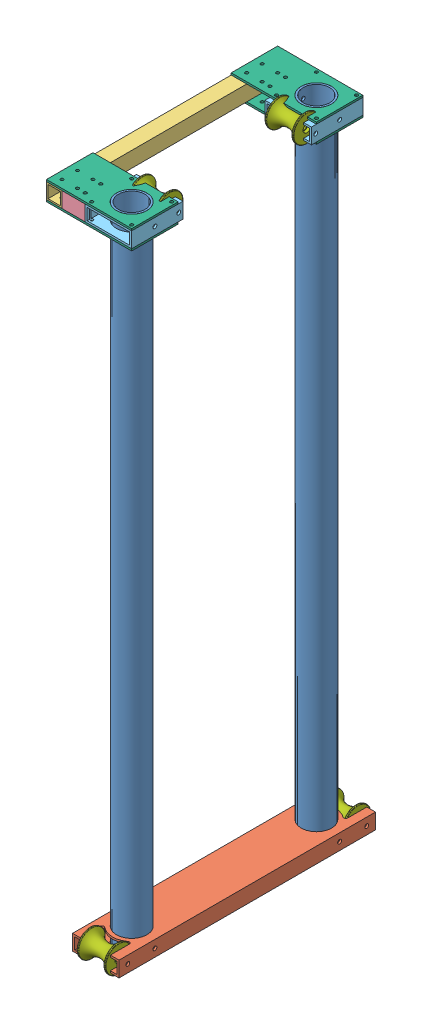
SolidWorks assembly 220-000 Second Stage Asm, configuration Default. Lengths in mm.
Overall size (139.7 1085.1 443.43).
17 component instances, 7 part files, 16 mates.
Components (placement in the parent):
- 220-002 Rod-1: 220-002 Rod [Default] at (79.1621 3.4691 -166.1788) x (0 0 1) z (-1 0 0) size (49.94 1054.1 49.94)
- 220-002 Rod-2: 220-002 Rod [Default] at (79.1621 3.4691 136.7848) x (0.387844 0 0.921725) z (-0.921725 0 0.387844) size (49.94 1054.1 49.94)
- 220-001n Second stage base-1: 220-001n Second stage base [Default] at (79.1621 16.1691 -225.0433) size (76.2 25.4 420.69)
- 221-000 Asm-1: 221-000 Asm [Default] at (2.9621 1028.9941 -14.697) x (-1 0 0) z (0 0 -1) size (139.7 61.76 379.16)
  - 221-003-1: 221-003 [Default] at origin size (25.4 25.4 379.16)
  - 221-002-1: 221-002 [Default] at (-19.05 25.4 189.5818) x (0 0 -1) z (-1 0 0) size (50.8 25.4 38.1)
  - 221-001-1: 221-001 [Default] at (-114.3 25.4 140.3058) x (1 0 0) z (0 1 0) size (76.2 84.26 25.4)
  - 221-001-2: 221-001 [Default] at (-114.3 0 -140.3058) x (1 0 0) z (0 -1 0) size (76.2 84.26 25.4)
  - 221-002-2: 221-002 [Default] at (-19.05 0 -189.5818) x (0 0 1) z (-1 0 0) size (50.8 25.4 38.1)
  - 221-004-1: 221-004 [Rev 1.1] at (0 25.4 0) x (1 0 0) z (0 1 0) size (139.7 76.2 3.17)
  - 221-004-2: 221-004 [Rev 1.1] at (0 25.4 302.9636) x (1 0 0) z (0 1 0) size (139.7 76.2 3.17)
  - 221-004-3: 221-004 [Rev 1.1] at (0 -3.175 0) x (1 0 0) z (0 1 0) size (139.7 76.2 3.17)
  - 221-004-4: 221-004 [Rev 1.1] at (0 -3.175 302.9636) x (1 0 0) z (0 1 0) size (139.7 76.2 3.17)
  - 200-001 Roller 3-1: 200-001 Roller 3 [Default] at (-76.2 12.7 -112.3658) x (0 -1 0) z (0 0 1) size (43.94 46.98 43.94)
  - 200-001 Roller 3-2: 200-001 Roller 3 [Default] at (-76.2 12.7 112.3658) x (0 -0.780395 0.625287) z (0 0.625287 0.780395) size (43.94 46.98 43.94)
- 200-001 Roller 3-1: 200-001 Roller 3 [Default] at (79.1621 16.1691 -210.6288) x (0 0.381849 -0.924225) z (0 -0.924225 -0.381849) size (43.94 46.98 43.94)
- 200-001 Roller 3-2: 200-001 Roller 3 [Default] at (79.1621 16.1691 181.2348) x (0 0.999115 0.042073) z (0 -0.042073 0.999115) size (43.94 46.98 43.94)
Mates (geometry in assembly coordinates):
- Concentric2: concentric: cylinder of 220-002 Rod-2 through (79.1621 1057.5691 136.7848) axis (0 -1 0) radius 24.972; cylinder of 221-000 Asm-1/221-004-1 through (79.1621 1057.5691 136.7848) axis (0 -1 0) radius 24.972
- Coincident1: coincident: plane of 220-002 Rod-2 through (79.1621 3.4691 136.7848) normal (0 -1 0); plane of 220-001n Second stage base-1 through (41.0621 3.4691 195.6493) normal (0 -1 0)
- Coincident2: coincident: plane of 220-002 Rod-1 through (79.1621 3.4691 -166.1788) normal (0 -1 0); plane of 220-001n Second stage base-1 through (41.0621 3.4691 195.6493) normal (0 -1 0)
- Coincident3: coincident: plane of 220-002 Rod-1 through (79.1621 1057.5691 -166.1788) normal (0 1 0); plane of 221-000 Asm-1/221-004-2 through (2.9621 1057.5691 -317.6606) normal (0 1 0)
- Concentric3: concentric: cylinder of 220-002 Rod-2 through (79.1621 1057.5691 136.7848) axis (0 -1 0) radius 24.972; cylinder of 220-001n Second stage base-1 through (79.1621 3.4691 136.7848) axis (0 1 0) radius 24.972
- Concentric4: concentric: circle of 220-001n Second stage base-1; circle of ?
- Concentric5: concentric: cylinder of 220-002 Rod-1 through (79.1621 1057.5691 -166.1788) axis (0 -1 0) radius 24.972; cylinder of 220-001n Second stage base-1 through (79.1621 3.4691 -166.1788) axis (0 1 0) radius 24.972
- Concentric6: concentric: circle of 220-001n Second stage base-1; circle of ?
- Width1: width: plane of ? through (96.8151 16.1691 175.7738) normal (1 0 0); plane of ? through (61.5091 16.1691 175.7738) normal (-1 0 0); plane of 220-001n Second stage base-1 through (56.3021 16.1691 203.4598) normal (1 0 0); plane of 220-001n Second stage base-1 through (102.0221 16.1691 203.4598) normal (-1 0 0)
- Width2: width: plane of ? through (61.5091 16.1691 -181.6042) normal (-1 0 0); plane of ? through (96.8151 16.1691 -181.6042) normal (1 0 0); plane of 220-001n Second stage base-1 through (56.3021 16.1691 203.4598) normal (1 0 0); plane of 220-001n Second stage base-1 through (102.0221 16.1691 203.4598) normal (-1 0 0)
- Concentric7: concentric: cylinder of 200-001 Roller 3-2 through (55.6718 16.1691 181.2348) axis (-1 0 0) radius 6.35; cylinder of 220-001n Second stage base-1 through (41.0621 16.1691 181.2348) axis (1 0 0) radius 3.175
- Width3: width: plane of 200-001 Roller 3-2 through (102.6523 16.1691 181.2348) normal (1 0 0); plane of 200-001 Roller 3-2 through (55.6718 16.1691 181.2348) normal (-1 0 0); plane of 220-001n Second stage base-1 through (114.0871 16.1691 195.6493) normal (-1 0 0); plane of 220-001n Second stage base-1 through (44.2371 16.1691 195.6493) normal (1 0 0)
- Coincident4: coincident: plane of 200-001 Roller 3-1 through (102.6523 16.1691 -210.6288) normal (1 0 0); plane of 200-001 Roller 3-2 through (102.6523 16.1691 181.2348) normal (1 0 0)
- Concentric8: concentric: cylinder of 220-001n Second stage base-1 through (41.0621 16.1691 -210.6288) axis (1 0 0) radius 3.175; cylinder of 200-001 Roller 3-1 through (102.6523 16.1691 -210.6288) axis (1 0 0) radius 6.35
- Concentric9: concentric: cylinder of 220-002 Rod-1 through (79.1621 1057.5691 -166.1788) axis (0 -1 0) radius 24.972; cylinder of 221-000 Asm-1/221-001-1 through (79.1621 1081.5721 -166.1788) axis (0 -1 0) radius 24.972
- Concentric10: concentric: cylinder of 220-002 Rod-1 through (104.1341 16.1691 -166.1788) axis (-1 0 0) radius 3.175; cylinder of 220-001n Second stage base-1 through (41.0621 16.1691 -166.1788) axis (1 0 0) radius 3.175
